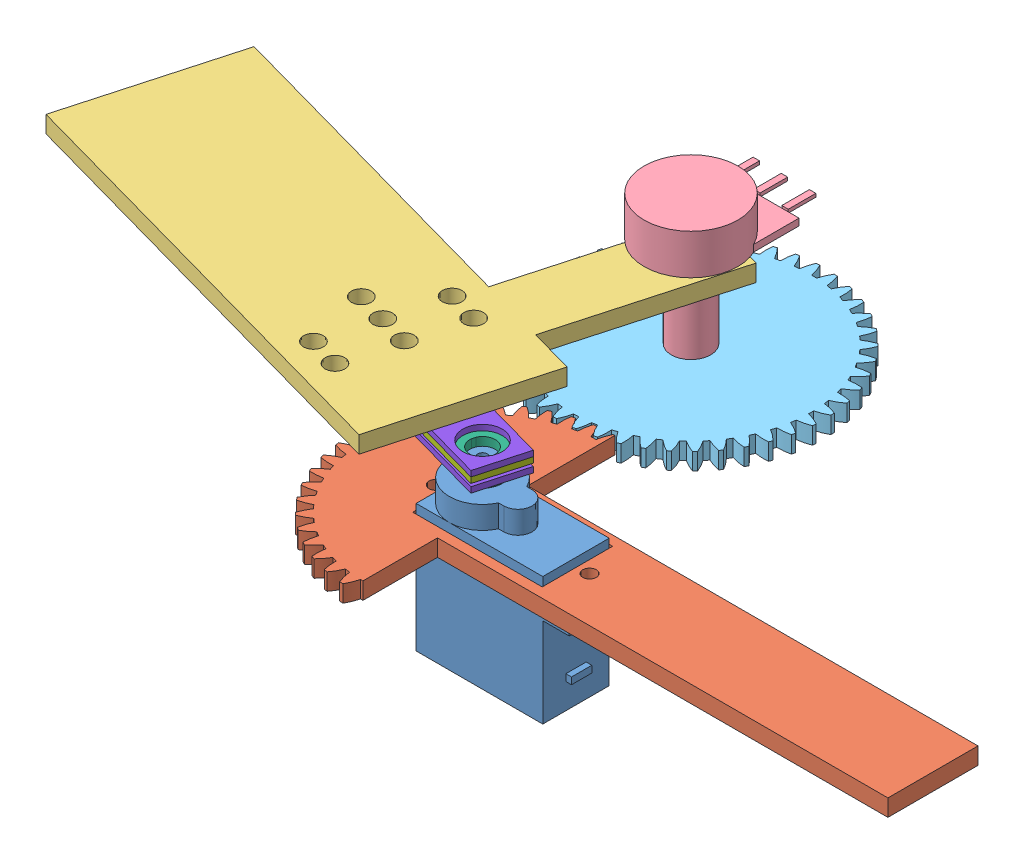
SolidWorks assembly pwEXO縮小測試模型完整組合[01-v1.0], configuration Default. Lengths in mm.
Overall size (165.91 44.56 101).
10 component instances, 8 part files, 12 mates.
Components (placement in the parent):
- 伺服馬達SG90[01-v1.0]-1: 伺服馬達SG90[01-v1.0] [Default] at (-18.2755 24.865 69.3028) size (31.9 29.9 11.8)
- 伺服馬達SG90固定板-小腿[01-v3.0]-1: 伺服馬達SG90固定板-小腿[01-v3.0] [Default] at (-79.4045 46.265 -21.3482) x (1 0 0) z (0 -1 0) size (103.49 46.96 3)
- 伺服馬達SG90固定板-大腿[01-v1.0]-1: 伺服馬達SG90固定板-大腿[01-v1.0] [Default] at (-66.9733 57.265 57.2214) x (-0.963286 0 -0.268476) z (0.268476 0 -0.963286) size (80 3 61.78)
- 可變電阻[01-v1.0]-1: 可變電阻[01-v1.0] [Default] at (-30.9956 69.425 24.9104) x (1 0 0) z (0 -1 0) size (16.66 24.93 29.29)
- 可變電阻齒輪[01-v2.0]-1: 可變電阻齒輪[01-v2.0] [Default] at (-132.9693 43.265 55.4109) x (0.746135 0 0.665795) z (0 1 0) size (46.99 46.96 3)
- 伺服馬達SG90用轉軸片壓克力固定組合[01-v1.0]-1: 伺服馬達SG90用轉軸片壓克力固定組合[01-v1.0] [Default] at (-29.3846 44.9741 85.1039) x (-0.963286 0 -0.268476) z (0.268476 0 -0.963286) size (40 4.9 9)
  - 伺服馬達SG90用轉軸片[01-v1.0]-1: 伺服馬達SG90用轉軸片[01-v1.0] [Default] at (-1.3055 11.2909 16.7672) size (19.5 3.9 7)
  - 伺服馬達SG90用轉軸片壓克力套[01-v1.0]-1: 伺服馬達SG90用轉軸片壓克力套[01-v1.0] [Default] at (13.6945 10.2909 16.7672) size (40 1 9)
  - 伺服馬達SG90用轉軸片壓克力套[02-v1.0]-1: 伺服馬達SG90用轉軸片壓克力套[02-v1.0] [Default] at (13.6945 8.7909 16.7672) size (40 1 9)
  - 伺服馬達SG90用轉軸片壓克力套[02-v1.0]-2: 伺服馬達SG90用轉軸片壓克力套[02-v1.0] [Default] at (13.6945 11.2909 16.7672) size (40 1 9)
Mates (geometry in assembly coordinates):
- Coincident3: coincident anti-aligned: plane of 伺服馬達SG90[01-v1.0]-1 through (-18.2755 43.265 69.3028) normal (0 1 0); plane of 伺服馬達SG90固定板-小腿[01-v3.0]-1 through (-33.8023 43.265 66.441) normal (0 -1 0)
- Concentric5: concentric aligned: cylinder of 伺服馬達SG90[01-v1.0]-1 through (-31.9255 43.265 69.3028) axis (0 -1 0) radius 1; cylinder of 伺服馬達SG90固定板-小腿[01-v3.0]-1 through (-31.9255 46.265 69.3028) axis (0 -1 0) radius 1.2
- Concentric6: concentric aligned: cylinder of 伺服馬達SG90[01-v1.0]-1 through (-4.6255 43.265 69.3028) axis (0 -1 0) radius 1; cylinder of 伺服馬達SG90固定板-小腿[01-v3.0]-1 through (-4.6255 46.265 69.3028) axis (0 -1 0) radius 1.2
- Concentric11: concentric anti-aligned: cylinder of 伺服馬達SG90固定板-大腿[01-v1.0]-1 through (-30.9956 60.265 24.9104) axis (0 -1 0) radius 3.75; cylinder of 可變電阻[01-v1.0]-1 through (-30.9956 40.135 24.9104) axis (0 1 0) radius 3.5
- Distance2: distance = 2 mm anti-aligned: plane of 伺服馬達SG90固定板-大腿[01-v1.0]-1 through (-66.9733 60.265 57.2214) normal (0 1 0); plane of 可變電阻[01-v1.0]-1 through (-30.9956 62.265 24.9104) normal (0 -1 0)
- Coincident9: coincident aligned: plane of 可變電阻齒輪[01-v2.0]-1 through (-40.4943 43.265 20.2701) normal (0 -1 0); plane of 伺服馬達SG90固定板-小腿[01-v3.0]-1 through (-33.8023 43.265 66.441) normal (0 -1 0)
- GearMate1: gear = 45 : 45 mm: circle of 可變電阻齒輪[01-v2.0]-1; circle of 伺服馬達SG90固定板-小腿[01-v3.0]-1
- Concentric15: concentric anti-aligned: cylinder of 伺服馬達SG90[01-v1.0]-1 through (-23.6255 54.765 69.3028) axis (0 -1 0) radius 2.3; cylinder of 伺服馬達SG90用轉軸片壓克力固定組合[01-v1.0]-1/伺服馬達SG90用轉軸片[01-v1.0]-1 through (-23.6255 52.365 69.3028) axis (0 1 0) radius 2.25
- Concentric16: concentric aligned: cylinder of 伺服馬達SG90固定板-大腿[01-v1.0]-1 through (-53.4873 57.265 60.9801) axis (0 1 0) radius 1.75; cylinder of 伺服馬達SG90用轉軸片壓克力固定組合[01-v1.0]-1/伺服馬達SG90用轉軸片壓克力套[01-v1.0]-1 through (-53.4873 53.265 60.9801) axis (0 1 0) radius 1.75
- Coincident11: coincident anti-aligned: plane of 伺服馬達SG90固定板-大腿[01-v1.0]-1 through (-66.9733 57.265 57.2214) normal (0 -1 0); plane of 伺服馬達SG90用轉軸片壓克力固定組合[01-v1.0]-1/伺服馬達SG90用轉軸片壓克力套[02-v1.0]-2 through (-38.0747 57.265 65.2757) normal (0 1 0)
- Concentric17: concentric aligned: cylinder of 伺服馬達SG90固定板-大腿[01-v1.0]-1 through (-42.8912 57.265 63.9333) axis (0 1 0) radius 1.75; cylinder of 伺服馬達SG90用轉軸片壓克力固定組合[01-v1.0]-1/伺服馬達SG90用轉軸片壓克力套[01-v1.0]-1 through (-42.8912 53.265 63.9333) axis (0 1 0) radius 1.75
- Distance3: distance = 4.7 mm aligned: plane of 伺服馬達SG90[01-v1.0]-1 through (-18.2755 51.565 69.3028) normal (0 1 0); plane of 伺服馬達SG90用轉軸片壓克力固定組合[01-v1.0]-1/伺服馬達SG90用轉軸片[01-v1.0]-1 through (-23.6255 56.265 69.3028) normal (0 1 0)
